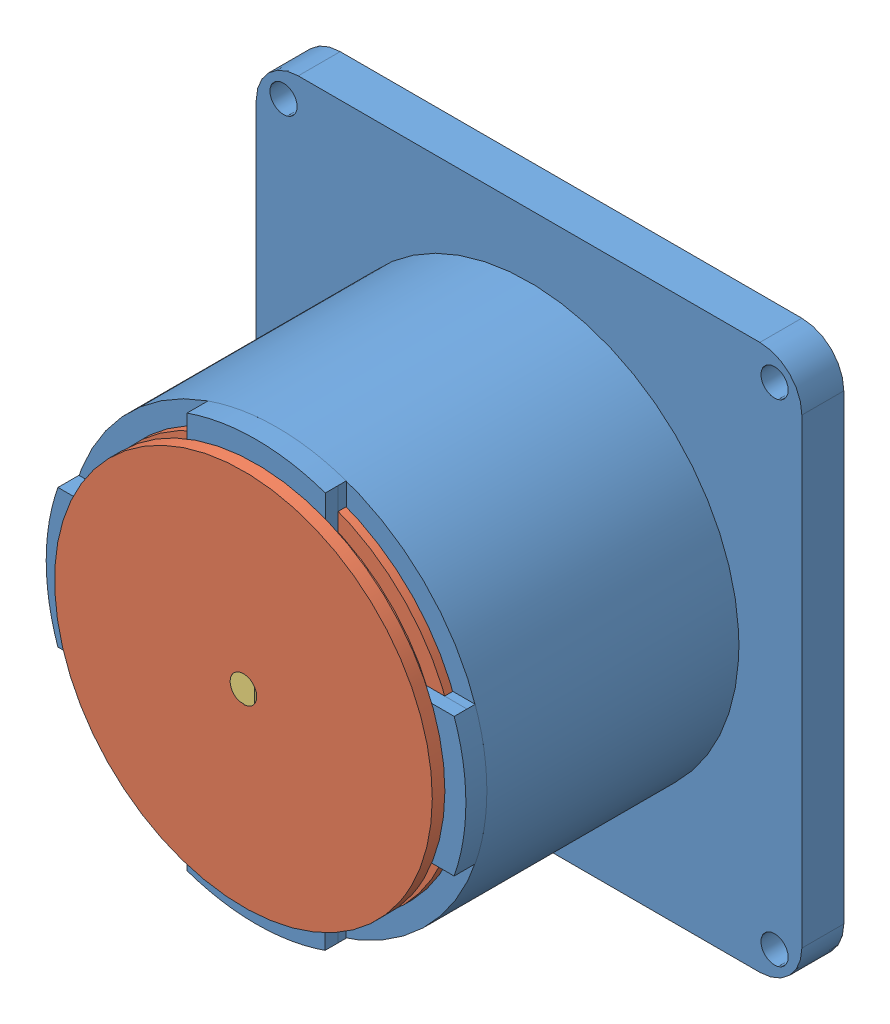
SolidWorks assembly 010, configuration Domyślna. Lengths in mm.
Overall size (130 130 78.05).
14 component instances, 6 part files, 22 mates.
Components (placement in the parent):
- 011-1: 011 [Domyślna] at (-12.9472 5.5241 130) size (130 130 75.05)
- 012-1: 012 [Domyślna] at (-12.9472 5.5241 208.05) x (0.859115 -0.511783 0) z (0 0 -1) size (90 90 8.6)
- 57cm12x-1: 57cm12x [Default] at (-12.9472 5.5241 185.05) x (0 -1 0) z (0 0 1) size (57.15 58.15 68)
  - 57cm12x_01-1: 57cm12x_01 [Default] at origin size (6.35 6.35 11.4)
  - 57cm12x_02-1: 57cm12x_02 [Default] at origin size (57.15 58.15 56.6)
- 024-1: 024 [Domyślna] at (10.6028 -18.0259 172.05) size (5 5 23)
- 024-2: 024 [Domyślna] at (10.6028 29.0741 172.05) size (5 5 23)
- 024-3: 024 [Domyślna] at (-36.4972 -18.0259 172.05) size (5 5 23)
- 024-4: 024 [Domyślna] at (-36.4972 29.0741 172.05) size (5 5 23)
- Seeger-1: Seeger [Domyślna] at (10.6028 -18.0259 189.55) size (6 6.84 0.5)
- Seeger-3: Seeger [Domyślna] at (-36.4972 29.0741 190.5833) size (6 6.84 0.5)
- Seeger-4: Seeger [Domyślna] at (-36.4972 -18.0259 189.55) x (0.999903 -0.013931 0) z (0 0 1) size (6 6.84 0.5)
- Seeger-5: Seeger [Domyślna] at (10.6028 29.0741 189.55) size (6 6.84 0.5)
- Seeger-6: Seeger [Domyślna] at (-36.4972 29.0741 189.55) size (6 6.84 0.5)
Mates (geometry in assembly coordinates):
- Wspólnie1: coincident anti-aligned: plane of Podstawa-1 through (-12.9472 5.5241 195.05) normal (0 0 -1); plane of 57cm12x-1/57cm12x_02-1 through (15.6278 -23.0509 195.05) normal (0 0 1)
- Koncentryczne1: concentric aligned: circle of Podstawa-1; circle of 57cm12x-1/57cm12x_02-1
- Wspólnie3: coincident anti-aligned: plane of Podstawa-1 through (-12.9472 5.5241 205.05) normal (0 0 1); plane of 012-1 through (-12.9472 5.5241 205.05) normal (0 0 -1)
- Równolegle1: parallel aligned: plane of 011-1 through (52.0528 60.5241 140) normal (1 0 0); plane of 57cm12x-1/57cm12x_02-1 through (15.5528 -22.9759 150.05) normal (1 0 0)
- Wspólnie5: coincident anti-aligned: plane of 011-1 through (-12.9472 5.5241 195.05) normal (0 0 -1); plane of 024-1 through (10.6028 -18.0259 195.05) normal (0 0 1)
- Wspólnie7: coincident anti-aligned: plane of 011-1 through (-12.9472 5.5241 195.05) normal (0 0 -1); plane of 024-2 through (10.6028 29.0741 195.05) normal (0 0 1)
- Wspólnie8: coincident anti-aligned: plane of 011-1 through (-12.9472 5.5241 195.05) normal (0 0 -1); plane of 024-3 through (-36.4972 -18.0259 195.05) normal (0 0 1)
- Wspólnie9: coincident anti-aligned: plane of 011-1 through (-12.9472 5.5241 195.05) normal (0 0 -1); plane of 024-4 through (-36.4972 29.0741 195.05) normal (0 0 1)
- Koncentryczne3: concentric aligned: circle of 57cm12x-1/57cm12x_02-1; circle of 024-2
- Koncentryczne4: concentric aligned: circle of 57cm12x-1/57cm12x_02-1; circle of 024-4
- Koncentryczne5: concentric aligned: circle of 57cm12x-1/57cm12x_02-1; circle of 024-3
- Koncentryczne8: concentric anti-aligned: circle of 024-4; circle of Seeger-3
- Koncentryczne10: concentric anti-aligned: circle of 024-3; circle of Seeger-4
- Koncentryczne13: concentric anti-aligned: circle of 024-1; circle of Seeger-1
- Koncentryczne14: concentric anti-aligned: circle of 024-2; circle of Seeger-5
- Koncentryczne15: concentric anti-aligned: circle of 024-4; circle of Seeger-6
- Wspólnie17: coincident anti-aligned: plane of 57cm12x-1/57cm12x_02-1 through (-36.9472 -18.4759 190.05) normal (0 0 -1); plane of Seeger-4 through (-36.4972 -18.0259 190.05) normal (0 0 1)
- Wspólnie18: coincident anti-aligned: plane of 57cm12x-1/57cm12x_02-1 through (-36.9472 29.5241 190.05) normal (0 0 -1); plane of Seeger-6 through (-36.4972 29.0741 190.05) normal (0 0 1)
- Wspólnie19: coincident anti-aligned: plane of 57cm12x-1/57cm12x_02-1 through (11.0528 29.5241 190.05) normal (0 0 -1); plane of Seeger-5 through (10.6028 29.0741 190.05) normal (0 0 1)
- Wspólnie20: coincident anti-aligned: plane of 57cm12x-1/57cm12x_02-1 through (11.0528 -18.4759 190.05) normal (0 0 -1); plane of Seeger-1 through (10.6028 -18.0259 190.05) normal (0 0 1)
- Równolegle3: parallel anti-aligned: plane of 011-1 through (-29.4027 -10.9759 200.05) normal (0 0 1); plane of 012-1 through (-12.9472 5.5241 199.45) normal (0 0 -1)
- Koncentryczne16: concentric anti-aligned: cylinder of 012-1; cylinder of 57cm12x-1/57cm12x_02-1 through (-12.9472 5.5241 196.65) axis (0 0 1) radius 19.05
